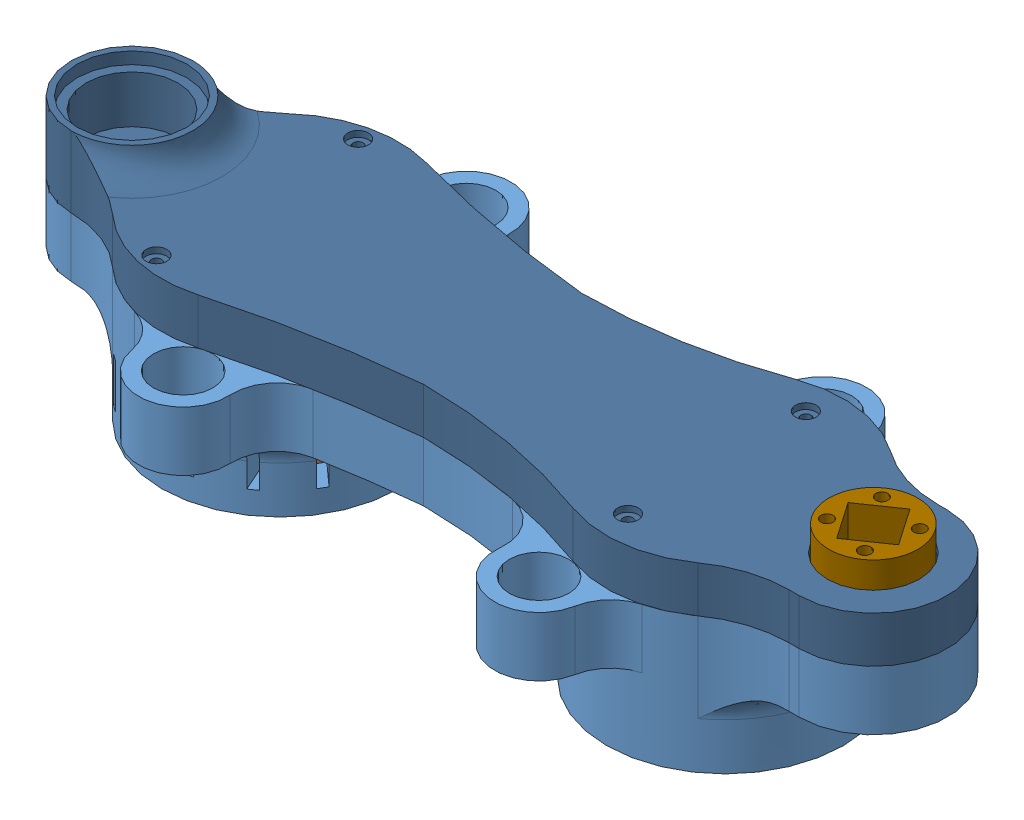
SolidWorks assembly front hip assembly, configuration Default. Lengths in mm.
Overall size (295.5 72.51 125.46).
13 component instances, 10 part files, 27 mates.
Components (placement in the parent):
- front hip-1: front hip [Default] at (0.3187 172.8353 234.9828) size (295.5 45.8 125.46)
- MAD5008IPE-1: MAD5008IPE [Default] at (0.3187 147.0353 234.9828) x (0.983291 0 -0.182042) z (0.182042 0 0.983291) size (56 29.3 56)
- GT2 15 Teeth motor-1: GT2 15 Teeth motor [Default] at (0.3187 174.4507 234.9828) x (0.983291 0 -0.182042) z (0.182042 0 0.983291) size (24 30 24)
- 15_45 pulley-1: 15_45 pulley [Default] at (108.3058 199.9066 223.9107) x (-0.827218 0 0.561881) z (0.561881 0 0.827218) size (34 30.5 34)
- W_617_8-1: W_617_8 [Default] at (109.9187 170.3353 234.9828) x (0 1 0) z (0.105818 0 0.994386) size (2.5 14.75 14.75)
- W_61706_2RZ-1: W_61706_2RZ [Default] at (200.3187 174.3353 234.9828) x (0 -1 0) z (0 0 1) size (4 46.12 46.12)
- encoder-1: encoder [Default] at (0.3187 191.6053 234.9828) x (0.010998 0 -0.99994) z (0 1 0) size (28.79 43.54 9.21)
- encoder holder-1: encoder holder [Default] at (0.3187 182.8353 234.9828) x (0 0 -1) z (1 0 0) size (70 5 40.98)
- knee joint 45T-1: knee joint 45T [Default] at (200.3187 183.8353 234.9828) x (0.822956 0 -0.568105) z (0.568105 0 0.822956) size (34 41.5 34)
- front hip cover-1: front hip cover [Default] at (0.3187 198.3353 234.9828) x (1 0 0) z (0 0 -1) size (295.5 26.71 80)
- W_617_8-2: W_617_8 [Default] at (109.9187 198.3353 234.9828) x (0 1 0) z (0.105818 0 0.994386) size (2.5 14.75 14.75)
- W_617_8-3: W_617_8 [Default] at (0.3187 198.3353 234.9828) x (0 1 0) z (0.933414 0 0.358801) size (2.5 14.75 14.75)
- W_61706_2RZ-2: W_61706_2RZ [Default] at (200.3187 200.8353 234.9828) x (0 -1 0) z (0 0 1) size (4 46.12 46.12)
Mates (geometry in assembly coordinates):
- Concentric1: concentric: cylinder of front hip-1 through (0.3187 187.8353 234.9828) axis (0 -1 0) radius 30; cylinder of MAD5008IPE-1 through (0.3187 172.8353 234.9828) axis (0 -1 0) radius 28
- Coincident1: coincident: plane of front hip-1 through (0.3187 172.8353 234.9828) normal (0 1 0); plane of MAD5008IPE-1 through (0.3187 172.8353 234.9828) normal (0 1 0)
- Concentric4: concentric: cylinder of MAD5008IPE-1 through (-1.0466 169.8353 227.6082) axis (0 1 0) radius 1.5; cylinder of GT2 15 Teeth motor-1 through (-1.0466 172.8353 227.6082) axis (0 1 0) radius 1.5
- Concentric5: concentric: cylinder of MAD5008IPE-1 through (1.684 169.8353 242.3575) axis (0 1 0) radius 1.5; cylinder of GT2 15 Teeth motor-1 through (1.684 172.8353 242.3575) axis (0 1 0) radius 1.5
- Coincident3: coincident: plane of MAD5008IPE-1 through (0.3187 172.8353 234.9828) normal (0 1 0); plane of GT2 15 Teeth motor-1 through (-11.4808 172.8353 237.1673) normal (0 -1 0)
- Concentric6: concentric: cylinder of front hip-1 through (109.9187 167.8353 234.9828) axis (0 1 0) radius 6; cylinder of 15_45 pulley-1 through (109.9187 174.8353 234.9828) axis (0 1 0) radius 17
- Coincident5: coincident: plane of GT2 15 Teeth motor-1 through (-4.3762 176.8353 235.852) normal (0 1 0); plane of 15_45 pulley-1 through (109.9187 176.8353 234.9828) normal (0 1 0)
- Concentric7: concentric: cylinder of front hip-1 through (109.9187 167.8353 234.9828) axis (0 1 0) radius 6; cylinder of W_617_8-1 through (109.9187 172.8353 234.9828) axis (0 1 0) radius 6
- Coincident6: coincident: plane of front hip-1 through (0.3187 172.8353 234.9828) normal (0 1 0); plane of W_617_8-1 through (105.792 172.8353 235.422) normal (0 1 0)
- Concentric8: concentric: cylinder of front hip-1 through (200.3187 167.8353 234.9828) axis (0 1 0) radius 18.5; cylinder of W_61706_2RZ-1 through (200.3187 124.3353 234.9828) axis (0 -1 0) radius 18.5
- Coincident8: coincident: plane of front hip-1 through (200.3187 170.3353 234.9828) normal (0 1 0); plane of W_61706_2RZ-1 through (215.5187 170.3353 234.9828) normal (0 -1 0)
- Concentric10: concentric: cylinder of front hip-1 through (0.3187 187.8353 234.9828) axis (0 -1 0) radius 30; cylinder of encoder holder-1 through (0.3187 187.8353 234.9828) axis (0 -1 0) radius 30
- Coincident9: coincident: plane of front hip-1 through (9.9018 182.8353 202.84) normal (-0.285714 0 0.958315); plane of encoder holder-1 through (9.9018 187.8353 202.84) normal (0.285714 0 -0.958315)
- Coincident10: coincident: plane of front hip-1 through (0.3187 182.8353 234.9828) normal (0 1 0); plane of encoder holder-1 through (0.3187 182.8353 234.9828) normal (0 -1 0)
- Coincident11: coincident: plane of encoder-1 through (28.2061 187.8353 249.6777) normal (0 -1 0); plane of encoder holder-1 through (0.3187 187.8353 234.9828) normal (0 1 0)
- Concentric11: concentric: cylinder of W_61706_2RZ-1 through (200.3187 124.3353 234.9828) axis (0 -1 0) radius 15; cylinder of knee joint 45T-1 through (200.3187 183.8353 234.9828) axis (0 1 0) radius 17
- Coincident13: coincident: plane of 15_45 pulley-1 through (113.8684 194.8353 232.3001) normal (0 -1 0); plane of knee joint 45T-1 through (200.3187 194.8353 234.9828) normal (0 -1 0)
- Coincident14: coincident: plane of front hip-1 through (0.3187 187.8353 234.9828) normal (0 1 0); plane of front hip cover-1 through (0.3187 187.8353 234.9828) normal (0 -1 0)
- Concentric12: concentric: cylinder of front hip cover-1 through (109.9187 203.3353 234.9828) axis (0 -1 0) radius 6; cylinder of W_617_8-2 through (109.9187 200.8353 234.9828) axis (0 1 0) radius 6
- Coincident15: coincident: plane of front hip cover-1 through (109.9187 200.8353 234.9828) normal (0 -1 0); plane of W_617_8-2 through (105.792 200.8353 235.422) normal (0 1 0)
- Concentric13: concentric: cylinder of GT2 15 Teeth motor-1 through (0.3187 174.5216 234.9828) axis (0 1 0) radius 4; cylinder of encoder-1 through (0.3187 191.9585 234.9828) axis (0 1 0) radius 2
- Concentric14: concentric: cylinder of front hip cover-1 through (0.3187 203.3353 234.9828) axis (0 -1 0) radius 6; cylinder of W_617_8-3 through (0.3187 200.8353 234.9828) axis (0 1 0) radius 6
- Coincident16: coincident: plane of front hip cover-1 through (0.3187 200.8353 234.9828) normal (0 -1 0); plane of W_617_8-3 through (-1.1703 200.8353 238.8565) normal (0 1 0)
- Concentric15: concentric: cylinder of front hip cover-1 through (200.3187 203.3353 234.9828) axis (0 -1 0) radius 18.5; cylinder of W_61706_2RZ-2 through (200.3187 150.8353 234.9828) axis (0 -1 0) radius 18.5
- Coincident17: coincident: plane of front hip cover-1 through (200.3187 200.8353 234.9828) normal (0 -1 0); plane of W_61706_2RZ-2 through (216.452 200.8353 234.9828) normal (0 1 0)
- Concentric16: concentric: cylinder of 15_45 pulley-1 through (109.9187 200.8353 234.9828) axis (0 -1 0) radius 4; cylinder of W_617_8-2 through (109.9187 248.3353 234.9828) axis (0 1 0) radius 4
- Concentric17: concentric: cylinder of knee joint 45T-1 through (200.3187 211.8353 234.9828) axis (0 -1 0) radius 15; cylinder of W_61706_2RZ-2 through (200.3187 150.8353 234.9828) axis (0 -1 0) radius 15
